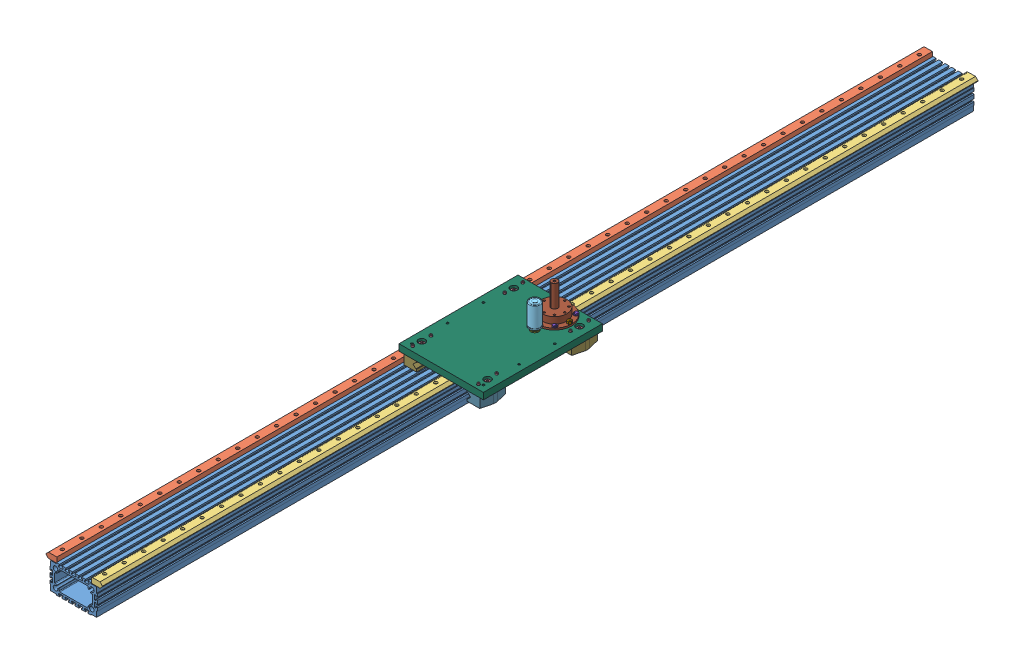
SolidWorks assembly 1xAURD6425W2_5SCWL+2xCHSS25L4046NK2_5SC43D43+HB25WL4051+CD+25W(CW), configuration Default. Lengths in mm.
Overall size (547.11 460.18 4051).
30 component instances, 15 part files, 57 mates.
Components (placement in the parent):
- HB 25 CD L4051C(264)_B-1: HB 25 CD L4051C(264)_B [Default] at (0 -95.5 -102.5) x (0 -1 0) z (0 0 1) size (130 220 4051)
- CHSS 25 L4046 NK C43 D43-1: CHSS 25 L4046 NK C43 D43 [Default] at (-97.7 -34.7 -100) x (0 0 1) z (-1 0 0) size (4046 25.4 50.4)
- CHSS 25 L4046 NK R2.5 C43 D43_M-1: CHSS 25 L4046 NK R2.5 C43 D43_M [Default] at (97.7 -34.7 -100) x (0 0 1) z (-1 0 0) size (4046 25.4 50.4)
- DIN912_M6x30_CW-1: DIN912_M6x30_CW [Default] at (68.1869 159.1782 2449.9005) size (11 46 11)
- DIN912_M6x30_CW-2: DIN912_M6x30_CW [Default] at (68.1869 159.1782 2365.9005) size (11 46 11)
- DIN912_M6x30_CW-3: DIN912_M6x30_CW [Default] at (68.1869 159.1782 2024.9005) x (-0.091029 0 -0.995848) z (0.995848 0 -0.091029) size (11 46 11)
- DIN912_M6x30_CW-4: DIN912_M6x30_CW [Default] at (68.1869 159.1782 1940.9005) x (0.999987 0 -0.005161) z (0.005161 0 0.999987) size (11 46 11)
- DIN912_M6x30_CW-5: DIN912_M6x30_CW [Default] at (372.0869 159.1782 2449.9005) x (0.254957 0 -0.966952) z (0.966952 0 0.254957) size (11 46 11)
- DIN912_M6x30_CW-6: DIN912_M6x30_CW [Default] at (372.0869 159.1782 2365.9005) x (-0.898442 0 -0.439093) z (0.439093 0 -0.898442) size (11 46 11)
- DIN912_M6x30_CW-7: DIN912_M6x30_CW [Default] at (372.0869 159.1782 1940.9005) x (-0.752669 0 -0.658399) z (0.658399 0 -0.752669) size (11 46 11)
- DIN912_M6x30_CW-8: DIN912_M6x30_CW [Default] at (372.0869 159.1782 2024.9005) x (0.193856 0 -0.98103) z (0.98103 0 0.193856) size (11 46 11)
- LAGD125-1: LAGD125 [Default] at (282.6369 157.3782 2100.4005) x (0.629012 0 0.777396) z (-0.777396 0 0.629012) size (52.2 116.5 52.2)
- HLPA 25 S_P-1: HLPA 25 S_P [Default] at (283.6369 119.3782 2100.4005) x (1 0 0) z (0 0 -1) size (44.35 18 44.35)
- HLPA 25 S_A-1: HLPA 25 S_A [Default] at (282.6369 119.3782 2100.4005) size (36 77 36)
- 2.5S_2.5H_N-1: 2.5S_2.5H_N [Default] at (226.6369 167.1782 2049.4005) x (-0.996585 0 0.082579) z (-0.082579 0 -0.996585) size (20 28.5 20)
- 2.5S_2.5H_N-2: 2.5S_2.5H_N [Default] at (226.6369 167.1782 1951.4005) x (0 0 -1) z (1 0 0) size (20 28.5 20)
- 2.5S_2.5H_N-3: 2.5S_2.5H_N [Default] at (324.6369 167.1782 2049.4005) x (-0.763815 0 -0.645435) z (0.645435 0 -0.763815) size (20 28.5 20)
- 2.5S_2.5H_N-4: 2.5S_2.5H_N [Default] at (324.6369 167.1782 1951.4005) x (0.002291 0 -0.999997) z (0.999997 0 0.002291) size (20 28.5 20)
- HDF 25S_B-1: HDF 25S_B [Default] at (345.6369 159.1782 2000.4005) x (-0.440006 0 -0.897995) z (0.897995 0 -0.440006) size (19.63 31 17)
- HP 25 X 20-1: HP 25 X 20 [Default] at (273.6369 100.1782 2000.4005) x (-0.498597 0 0.866834) z (0 -1 0) size (55.04 55.04 33.01)
- HDF 25S 20_M-1: HDF 25S 20_M [Default] at (273.6369 133.1782 2000.4005) x (0 0 -1) z (1 0 0) size (160 193.5 160)
- CW_64_M5 stainless steel cap screws DIN912 with washer_none_2-1: CW_64_M5 stainless steel cap screws DIN912 with washer_none_2 [Default] at (68.1869 129.1782 2407.9005) x (0 0 1) z (1 0 0) size (119 54 72.2)
- THJR_64_C_9-1: THJR_64_C_9 [Default] at (68.1869 129.1782 2407.9005) x (1 0 0) z (0 0 -1) size (64 62.5 64)
- CW_64_M5 stainless steel cap screws DIN912 with washer_none-1: CW_64_M5 stainless steel cap screws DIN912 with washer_none [Default] at (68.1869 129.1782 1982.9005) x (0 0 1) z (1 0 0) size (119 54 72.2)
- THJR_64_C_9-2: THJR_64_C_9 [Default] at (68.1869 129.1782 1982.9005) x (-0.247581 0 -0.968867) z (-0.968867 0 0.247581) size (64 62.5 64)
- CW_64_M5 stainless steel cap screws DIN912 with washer_none-2: CW_64_M5 stainless steel cap screws DIN912 with washer_none [Default] at (372.0869 129.1782 2407.9005) x (0 0 -1) z (-1 0 0) size (119 54 72.2)
- THJR_64_C_9-3: THJR_64_C_9 [Default] at (372.0869 129.1782 2407.9005) x (0.999567 0 -0.029434) z (-0.029434 0 -0.999567) size (64 62.5 64)
- CW_64_M5 stainless steel cap screws DIN912 with washer_none_2-2: CW_64_M5 stainless steel cap screws DIN912 with washer_none_2 [Default] at (372.0869 129.1782 1982.9005) x (0 0 -1) z (-1 0 0) size (119 54 72.2)
- THJR_64_C_9-4: THJR_64_C_9 [Default] at (372.0869 129.1782 1982.9005) x (0.81504 0 -0.579404) z (-0.579404 0 -0.81504) size (64 62.5 64)
- AURD 64 25W 2.5S CW L_P-1: AURD 64 25W 2.5S CW L_P [Default] at (220.1369 129.1782 2000.4005) size (390 30 550)
Mates (geometry in assembly coordinates):
- Concentric1: concentric anti-aligned: cylinder of CW_64_M5 stainless steel cap screws DIN912 with washer_none_2-1 through (68.1869 129.1782 2449.9005) axis (0 1 0) radius 2.067; cylinder of AURD 64 25W 2.5S CW L_P-1 through (68.1869 129.1782 2449.9005) axis (0 -1 0) radius 3.5
- Concentric2: concentric anti-aligned: cylinder of CW_64_M5 stainless steel cap screws DIN912 with washer_none_2-1 through (68.1869 129.1782 2365.9005) axis (0 1 0) radius 2.067; cylinder of AURD 64 25W 2.5S CW L_P-1 through (68.1869 129.1782 2365.9005) axis (0 -1 0) radius 3.5
- Coincident1: coincident anti-aligned: plane of CW_64_M5 stainless steel cap screws DIN912 with washer_none_2-1 through (30.8205 129.1782 2348.4005) normal (0 1 0); plane of AURD 64 25W 2.5S CW L_P-1 through (25.1369 129.1782 1920.4005) normal (0 -1 0)
- Concentric3: concentric aligned: cylinder of DIN912_M6x30_CW-2 through (68.1869 119.1782 2365.9005) axis (0 -1 0) radius 3; cylinder of AURD 64 25W 2.5S CW L_P-1 through (68.1869 129.1782 2365.9005) axis (0 -1 0) radius 3.5
- Concentric4: concentric aligned: cylinder of DIN912_M6x30_CW-1 through (68.1869 119.1782 2449.9005) axis (0 -1 0) radius 3; cylinder of AURD 64 25W 2.5S CW L_P-1 through (68.1869 129.1782 2449.9005) axis (0 -1 0) radius 3.5
- Coincident2: coincident anti-aligned: plane of DIN912_M6x30_CW-1 through (62.6869 159.1782 2444.4005) normal (0 -1 0); plane of AURD 64 25W 2.5S CW L_P-1 through (25.1369 159.1782 2470.4005) normal (0 1 0)
- Coincident3: coincident anti-aligned: plane of DIN912_M6x30_CW-2 through (62.6869 159.1782 2360.4005) normal (0 -1 0); plane of AURD 64 25W 2.5S CW L_P-1 through (25.1369 159.1782 2470.4005) normal (0 1 0)
- Concentric5: concentric anti-aligned: cylinder of THJR_64_C_9-1 through (68.1869 151.6782 2407.9005) axis (0 1 0) radius 12; cylinder of AURD 64 25W 2.5S CW L_P-1 through (68.1869 129.1782 2407.9005) axis (0 -1 0) radius 16
- Coincident4: coincident anti-aligned: plane of THJR_64_C_9-1 through (53.9268 138.1782 2393.9005) normal (0 -1 0); plane of AURD 64 25W 2.5S CW L_P-1 through (51.8897 138.1782 2391.9005) normal (0 1 0)
- Concentric7: concentric anti-aligned: cylinder of CW_64_M5 stainless steel cap screws DIN912 with washer_none-1 through (68.1869 129.1782 2024.9005) axis (0 1 0) radius 2.067; cylinder of AURD 64 25W 2.5S CW L_P-1 through (68.1869 129.1782 2024.9005) axis (0 -1 0) radius 3.5
- Concentric8: concentric anti-aligned: cylinder of CW_64_M5 stainless steel cap screws DIN912 with washer_none-1 through (68.1869 129.1782 1940.9005) axis (0 1 0) radius 2.067; cylinder of AURD 64 25W 2.5S CW L_P-1 through (68.1869 129.1782 1940.9005) axis (0 -1 0) radius 3.5
- Coincident5: coincident anti-aligned: plane of CW_64_M5 stainless steel cap screws DIN912 with washer_none-1 through (30.8205 129.1782 1923.4005) normal (0 1 0); plane of AURD 64 25W 2.5S CW L_P-1 through (25.1369 129.1782 1920.4005) normal (0 -1 0)
- Concentric9: concentric aligned: cylinder of DIN912_M6x30_CW-4 through (68.1869 119.1782 1940.9005) axis (0 -1 0) radius 3; cylinder of AURD 64 25W 2.5S CW L_P-1 through (68.1869 129.1782 1940.9005) axis (0 -1 0) radius 3.5
- Concentric10: concentric aligned: cylinder of DIN912_M6x30_CW-3 through (68.1869 119.1782 2024.9005) axis (0 -1 0) radius 3; cylinder of AURD 64 25W 2.5S CW L_P-1 through (68.1869 129.1782 2024.9005) axis (0 -1 0) radius 3.5
- Coincident6: coincident anti-aligned: plane of DIN912_M6x30_CW-3 through (63.2104 159.1782 2030.8783) normal (0 -1 0); plane of AURD 64 25W 2.5S CW L_P-1 through (25.1369 159.1782 2470.4005) normal (0 1 0)
- Coincident7: coincident anti-aligned: plane of DIN912_M6x30_CW-4 through (62.6586 159.1782 1935.429) normal (0 -1 0); plane of AURD 64 25W 2.5S CW L_P-1 through (25.1369 159.1782 2470.4005) normal (0 1 0)
- Concentric11: concentric anti-aligned: cylinder of THJR_64_C_9-2 through (68.1869 151.6782 1982.9005) axis (0 1 0) radius 8; cylinder of AURD 64 25W 2.5S CW L_P-1 through (68.1869 129.1782 1982.9005) axis (0 -1 0) radius 16
- Coincident8: coincident anti-aligned: plane of THJR_64_C_9-2 through (58.1533 138.1782 2000.1828) normal (0 -1 0); plane of AURD 64 25W 2.5S CW L_P-1 through (51.8897 138.1782 1966.9005) normal (0 1 0)
- Concentric12: concentric anti-aligned: cylinder of CW_64_M5 stainless steel cap screws DIN912 with washer_none-2 through (372.0869 129.1782 2449.9005) axis (0 1 0) radius 2.067; cylinder of AURD 64 25W 2.5S CW L_P-1 through (372.0869 129.1782 2449.9005) axis (0 -1 0) radius 3.5
- Concentric15: concentric anti-aligned: cylinder of CW_64_M5 stainless steel cap screws DIN912 with washer_none-2 through (372.0869 129.1782 2365.9005) axis (0 1 0) radius 2.067; cylinder of AURD 64 25W 2.5S CW L_P-1 through (372.0869 129.1782 2365.9005) axis (0 -1 0) radius 3.5
- Coincident9: coincident anti-aligned: plane of CW_64_M5 stainless steel cap screws DIN912 with washer_none-2 through (409.4533 129.1782 2467.4005) normal (0 1 0); plane of AURD 64 25W 2.5S CW L_P-1 through (25.1369 129.1782 1920.4005) normal (0 -1 0)
- Concentric16: concentric aligned: cylinder of DIN912_M6x30_CW-6 through (372.0869 119.1782 2365.9005) axis (0 -1 0) radius 3; cylinder of AURD 64 25W 2.5S CW L_P-1 through (372.0869 129.1782 2365.9005) axis (0 -1 0) radius 3.5
- Concentric17: concentric aligned: cylinder of DIN912_M6x30_CW-5 through (372.0869 119.1782 2449.9005) axis (0 -1 0) radius 3; cylinder of AURD 64 25W 2.5S CW L_P-1 through (372.0869 129.1782 2449.9005) axis (0 -1 0) radius 3.5
- Coincident10: coincident anti-aligned: plane of DIN912_M6x30_CW-6 through (374.6133 159.1782 2373.257) normal (0 -1 0); plane of AURD 64 25W 2.5S CW L_P-1 through (25.1369 159.1782 2470.4005) normal (0 1 0)
- Coincident11: coincident anti-aligned: plane of DIN912_M6x30_CW-5 through (365.3664 159.1782 2453.8165) normal (0 -1 0); plane of AURD 64 25W 2.5S CW L_P-1 through (25.1369 159.1782 2470.4005) normal (0 1 0)
- Concentric18: concentric anti-aligned: cylinder of THJR_64_C_9-3 through (372.0869 151.6782 2407.9005) axis (0 1 0) radius 12; cylinder of AURD 64 25W 2.5S CW L_P-1 through (372.0869 129.1782 2407.9005) axis (0 -1 0) radius 16
- Coincident12: coincident anti-aligned: plane of THJR_64_C_9-3 through (357.4209 138.1782 2394.3263) normal (0 -1 0); plane of AURD 64 25W 2.5S CW L_P-1 through (355.7897 138.1782 2391.9005) normal (0 1 0)
- Concentric19: concentric anti-aligned: cylinder of CW_64_M5 stainless steel cap screws DIN912 with washer_none_2-2 through (372.0869 129.1782 2024.9005) axis (0 1 0) radius 2.067; cylinder of AURD 64 25W 2.5S CW L_P-1 through (372.0869 129.1782 2024.9005) axis (0 -1 0) radius 3.5
- Concentric20: concentric anti-aligned: cylinder of CW_64_M5 stainless steel cap screws DIN912 with washer_none_2-2 through (372.0869 129.1782 1940.9005) axis (0 1 0) radius 2.067; cylinder of AURD 64 25W 2.5S CW L_P-1 through (372.0869 129.1782 1940.9005) axis (0 -1 0) radius 3.5
- Coincident13: coincident anti-aligned: plane of CW_64_M5 stainless steel cap screws DIN912 with washer_none_2-2 through (409.4533 129.1782 2042.4005) normal (0 1 0); plane of AURD 64 25W 2.5S CW L_P-1 through (25.1369 129.1782 1920.4005) normal (0 -1 0)
- Concentric21: concentric aligned: cylinder of DIN912_M6x30_CW-7 through (372.0869 119.1782 1940.9005) axis (0 -1 0) radius 3; cylinder of AURD 64 25W 2.5S CW L_P-1 through (372.0869 129.1782 1940.9005) axis (0 -1 0) radius 3.5
- Concentric22: concentric aligned: cylinder of DIN912_M6x30_CW-8 through (372.0869 119.1782 2024.9005) axis (0 -1 0) radius 3; cylinder of AURD 64 25W 2.5S CW L_P-1 through (372.0869 129.1782 2024.9005) axis (0 -1 0) radius 3.5
- Coincident14: coincident anti-aligned: plane of DIN912_M6x30_CW-7 through (372.6054 159.1782 1948.6614) normal (0 -1 0); plane of AURD 64 25W 2.5S CW L_P-1 through (25.1369 159.1782 2470.4005) normal (0 1 0)
- Coincident15: coincident anti-aligned: plane of DIN912_M6x30_CW-8 through (365.625 159.1782 2029.23) normal (0 -1 0); plane of AURD 64 25W 2.5S CW L_P-1 through (25.1369 159.1782 2470.4005) normal (0 1 0)
- Concentric23: concentric anti-aligned: cylinder of THJR_64_C_9-4 through (372.0869 151.6782 1982.9005) axis (0 1 0) radius 12; cylinder of AURD 64 25W 2.5S CW L_P-1 through (372.0869 129.1782 1982.9005) axis (0 -1 0) radius 16
- Coincident16: coincident anti-aligned: plane of THJR_64_C_9-4 through (352.3527 138.1782 1979.7523) normal (0 -1 0); plane of AURD 64 25W 2.5S CW L_P-1 through (355.7897 138.1782 1966.9005) normal (0 1 0)
- Concentric24: concentric aligned: cylinder of 2.5S_2.5H_N-4 through (324.6369 145.1782 1951.4005) axis (0 -1 0) radius 4.25; cylinder of HDF 25S 20_M-1 through (324.6369 167.1782 1951.4005) axis (0 -1 0) radius 4.5
- Coincident17: coincident anti-aligned: plane of 2.5S_2.5H_N-4 through (314.6134 167.1782 1961.6508) normal (0 -1 0); plane of HDF 25S 20_M-1 through (353.6369 167.1782 2081.287) normal (0 1 0)
- Concentric25: concentric aligned: cylinder of 2.5S_2.5H_N-3 through (324.6369 145.1782 2049.4005) axis (0 -1 0) radius 4.25; cylinder of HDF 25S 20_M-1 through (324.6369 167.1782 2049.4005) axis (0 -1 0) radius 4.5
- Coincident18: coincident anti-aligned: plane of 2.5S_2.5H_N-3 through (326.0294 167.1782 2063.6694) normal (0 -1 0); plane of HDF 25S 20_M-1 through (353.6369 167.1782 2081.287) normal (0 1 0)
- Concentric26: concentric aligned: cylinder of 2.5S_2.5H_N-1 through (226.6369 145.1782 2049.4005) axis (0 -1 0) radius 4.25; cylinder of HDF 25S 20_M-1 through (226.6369 167.1782 2049.4005) axis (0 -1 0) radius 4.5
- Concentric27: concentric aligned: cylinder of 2.5S_2.5H_N-2 through (226.6369 145.1782 1951.4005) axis (0 -1 0) radius 4.25; cylinder of HDF 25S 20_M-1 through (226.6369 167.1782 1951.4005) axis (0 -1 0) radius 4.5
- Coincident20: coincident anti-aligned: plane of 2.5S_2.5H_N-2 through (216.6369 167.1782 1961.6738) normal (0 -1 0); plane of HDF 25S 20_M-1 through (353.6369 167.1782 2081.287) normal (0 1 0)
- Coincident21: coincident anti-aligned: plane of 2.5S_2.5H_N-1 through (237.7008 167.1782 2058.518) normal (0 -1 0); plane of HDF 25S 20_M-1 through (353.6369 167.1782 2081.287) normal (0 1 0)
- Concentric28: concentric aligned: cylinder of 2.5S_2.5H_N-2 through (226.6369 145.1782 1951.4005) axis (0 -1 0) radius 4.25; cylinder of AURD 64 25W 2.5S CW L_P-1 through (226.6369 129.1782 1951.4005) axis (0 -1 0) radius 3.3235
- Concentric29: concentric aligned: cylinder of 2.5S_2.5H_N-4 through (324.6369 145.1782 1951.4005) axis (0 -1 0) radius 4.25; cylinder of AURD 64 25W 2.5S CW L_P-1 through (324.6369 129.1782 1951.4005) axis (0 -1 0) radius 3.3235
- Coincident22: coincident anti-aligned: plane of HDF 25S 20_M-1 through (193.6369 159.1782 2081.287) normal (0 -1 0); plane of AURD 64 25W 2.5S CW L_P-1 through (25.1369 159.1782 2470.4005) normal (0 1 0)
- Concentric30: concentric aligned: cylinder of HDF 25S_B-1 through (345.6369 147.1782 2000.4005) axis (0 -1 0) radius 3; cylinder of AURD 64 25W 2.5S CW L_P-1 through (345.6369 129.1782 2000.4005) axis (0 -1 0) radius 2.4585
- Coincident23: coincident anti-aligned: plane of HDF 25S_B-1 through (340.5266 167.1782 2013.8344) normal (0 -1 0); plane of HDF 25S 20_M-1 through (353.6369 167.1782 2081.287) normal (0 1 0)
- Concentric31: concentric anti-aligned: cylinder of HP 25 X 20-1 through (273.6369 133.1782 2000.4005) axis (0 1 0) radius 10; cylinder of HDF 25S 20_M-1 through (273.6369 106.1782 2000.4005) axis (0 -1 0) radius 10
- Coincident25: coincident anti-aligned: plane of HP 25 X 20-1 through (299.886 133.1782 1993.58) normal (0 1 0); plane of HDF 25S 20_M-1 through (219.1506 133.1782 2052.9005) normal (0 -1 0)
- Concentric33: concentric anti-aligned: cylinder of HLPA 25 S_P-1 through (283.6369 274.6042 2100.4005) axis (0 1 0) radius 7.5; cylinder of HLPA 25 S_A-1 through (283.6369 271.6042 2100.4005) axis (0 -1 0) radius 7.5
- Coincident27: coincident anti-aligned: plane of HLPA 25 S_P-1 through (261.4617 292.6042 2122.5757) normal (0 1 0); plane of HLPA 25 S_A-1 through (268.7805 292.6042 2088.4005) normal (0 -1 0)
- Concentric34: concentric aligned: circle of LAGD125-1; cylinder of HLPA 25 S_A-1 through (282.6369 301.6042 2100.4005) axis (0 -1 0) radius 10
- Coincident28: coincident anti-aligned: plane of LAGD125-1 through (286.2047 347.1042 2063.3164) normal (0 -1 0); plane of HLPA 25 S_A-1 through (265.3164 347.1042 2085.4005) normal (0 1 0)
- Concentric35: concentric aligned: cylinder of HLPA 25 S_A-1 through (282.6369 128.3782 2100.4005) axis (0 -1 0) radius 10; cylinder of AURD 64 25W 2.5S CW L_P-1 through (282.6369 159.1782 2100.4005) axis (0 -1 0) radius 10.5
- Coincident29: coincident anti-aligned: plane of HLPA 25 S_A-1 through (264.3025 159.1782 2082.4005) normal (0 -1 0); plane of AURD 64 25W 2.5S CW L_P-1 through (25.1369 159.1782 2470.4005) normal (0 1 0)
